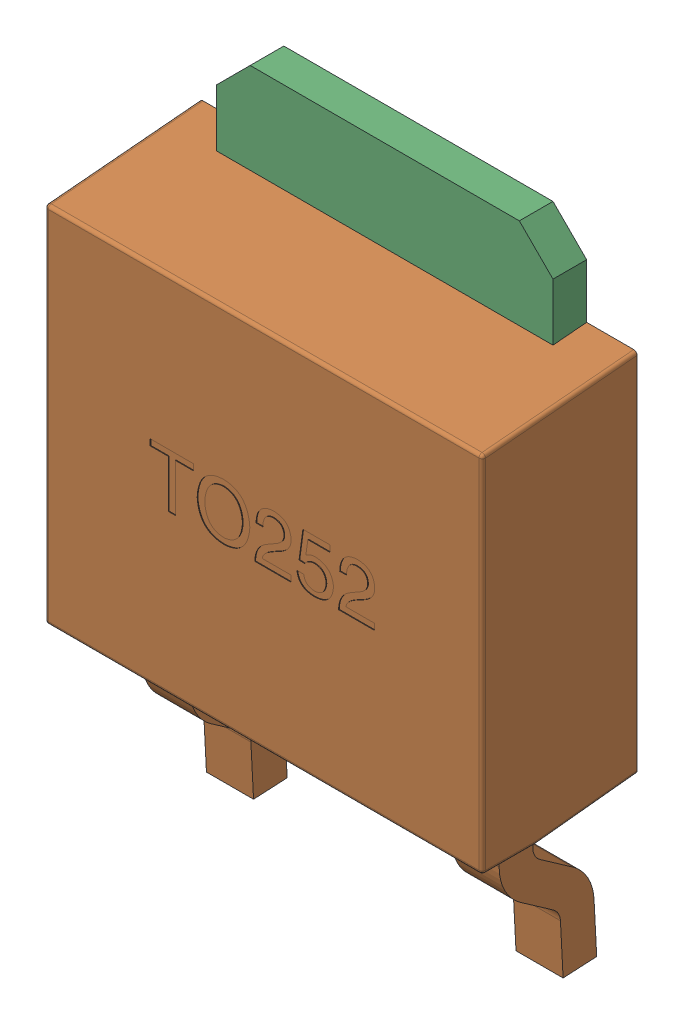
SolidWorks assembly MTG2, configuration 默认. Lengths in mm.
Overall size (6.5 9.42 2.31).
3 component instances, 2 part files, 0 mates.
Components (placement in the parent):
- TO252-1: TO252 [默认] at (55.612 61.9891 0) size (6.5 9.42 2.31)
  - LOGO_-1: LOGO_ [默认] at (2.3503 3.4211 -0.0025) x (-1 0 0) z (0 0 -1) size (0.75 0.87 0.01)
  - TO252-1: TO252 [默认] at origin size (6.5 9.42 2.3)
